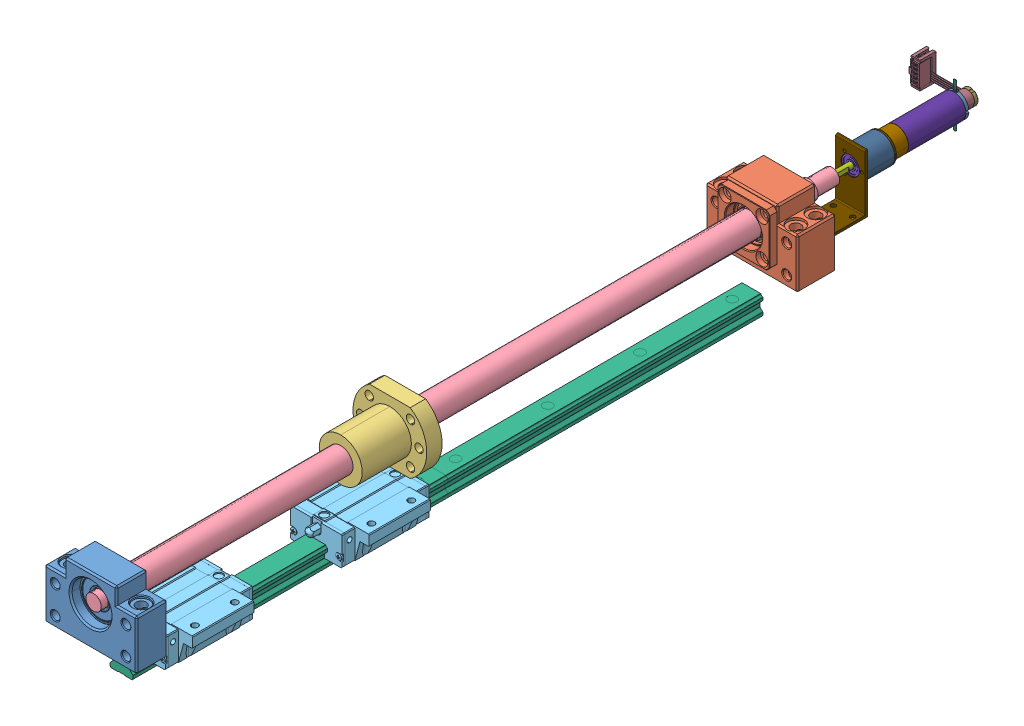
SolidWorks assembly ScrewAssembly_15cm_SIDE - Copy, configuration Default. Lengths in mm.
Overall size (61 69.4 574.65).
21 component instances, 18 part files, 27 mates.
Components (placement in the parent):
- BF12.step-1: BF12.step [Default] at (-30 0 240.25) size (60 43 20)
- BK12.step-1: BK12.step [Default] at (-30 0 -192.5) size (60 43 30.65)
- RM1605 Ball Nut STEP.step-1: RM1605 Ball Nut STEP.step [Default] at (-30 25 45.3506) x (0 0 1) z (0 -1 0) size (42 48 40)
- RM1605-1: RM1605 [Default] at (-30 25 248.25) x (-0.470167 -0.882577 0) z (0 0 -1) size (16 16 480.75)
- Carriage-1: Carriage [Default] at (-30 -24.4 145.8326) x (1 0 0) z (0 1 0) size (52 63.99 19.5)
- Rail-1: Rail [Default] at (-30 -24.4 230) x (1 0 0) z (0 1 0) size (15 205 12.5)
- Gantry Motor.stp-1: Gantry Motor.stp [Default] at (-30 25 -246) x (0 0 -1) z (1 0 0) size (91.9 29 40.5)
  - 0.stp-1: 0.stp [Default] at origin size (14.5 4 4)
  - 0-0.stp-1: 0-0.stp [Default] at origin size (4 12 12)
  - 0-1.stp-1: 0-1.stp [Default] at origin size (10.45 19 19)
  - 0-2.stp-1: 0-2.stp [Default] at origin size (17.97 19 19)
  - 0-3.stp-1: 0-3.stp [Default] at origin size (0.5 9.2 9.2)
  - 0-4.stp-1: 0-4.stp [Default] at origin size (2.88 10 10)
  - 0-5.stp-1: 0-5.stp [Default] at origin size (10.9 17.48 36)
  - 0-6.stp-1: 0-6.stp [Default] at origin size (2 15.64 15.71)
  - 0-7.stp-1: 0-7.stp [Default] at origin size (2.2 29 2.3)
  - 0-8.stp-1: 0-8.stp [Default] at origin size (2.1 15.8 15.45)
  - 0-9.stp-1: 0-9.stp [Default] at origin size (37.3 16 16)
- Motor Mounting Bracket-1: Motor Mounting Bracket [8982K701] at (-20.5 0 -226.95) x (0 0 -1) z (1 0 0) size (38.1 38.1 19)
- Rail-2: Rail [Default] at (-30 -24.4 25) x (1 0 0) z (0 1 0) size (15 205 12.5)
- Carriage-2: Carriage [Default] at (-30 -24.4 260.7326) x (1 0 0) z (0 1 0) size (52 63.99 19.5)
Mates (geometry in assembly coordinates):
- Coincident5: coincident: plane of assembly through (0 0 0) normal (0 1 0); plane of BK12.step-1 through (-60 0 -180) normal (0 -1 0); plane of assembly
- Coincident6: coincident: plane of assembly through (0 0 0) normal (0 1 0); plane of BF12.step-1 through (-60 0 250.25) normal (0 -1 0); plane of assembly
- Coincident8: coincident: plane of assembly through (0 0 0) normal (1 0 0); plane of BK12.step-1 through (0 0 -180) normal (1 0 0); plane of assembly
- Concentric7: concentric: cylinder of RM1605 Ball Nut STEP.step-1 through (-30 25 45.3506) axis (0 0 1) radius 8; cylinder of RM1605-1 through (-30 25 248.25) axis (0 0 1) radius 8
- Concentric8: concentric: cylinder of BK12.step-1 through (-30 25 -157.1571) axis (0 0 1) radius 6; cylinder of RM1605-1 through (-30 25 248.25) axis (0 0 1) radius 8
- Concentric9: concentric: cylinder of BF12.step-1 through (-30 25 244.456) axis (0 0 1) radius 5; cylinder of RM1605-1 through (-30 25 248.25) axis (0 0 1) radius 5
- Coincident11: coincident: plane of BF12.step-1 through (-30 30 236.25) normal (0 0 -1); plane of RM1605-1 through (-37.0606 28.7613 236.25) normal (0 0 1)
- Width1: width anti-aligned: plane of Carriage-1 through (-22.5 -14.3 31.1516) normal (-1 0 0); plane of Carriage-1 through (-37.5 -14.3 31.1516) normal (1 0 0); plane of Rail-1 through (-22.5 -14.3 25) normal (1 0 0); plane of Rail-1 through (-37.5 -14.3 25) normal (-1 0 0)
- Coincident22: coincident anti-aligned: plane of Carriage-1 through (-30 -11.9 31.1516) normal (0 -1 0); plane of Rail-1 through (-30 -11.9 25) normal (0 1 0)
- Coincident23: coincident: plane of RM1605 Ball Nut STEP.step-1 through (-30 25 45.3506) normal (0 0 -1); point of Carriage-1
- Width2: width: plane of BK12.step-1 through (0 0 -180) normal (1 0 0); plane of BK12.step-1 through (-60 32.5 -180) normal (-1 0 0); plane of Carriage-1 through (-56 -3.4 74.9316) normal (-1 0 0); plane of Carriage-1 through (-4 -3.9 55.0316) normal (1 0 0)
- Distance1: distance = 25.4 mm: cylinder of RM1605 Ball Nut STEP.step-1 through (-30 25 87.3506) axis (0 0 -1) radius 14; plane of Carriage-1 through (-30 -0.4 55.0316) normal (0 1 0)
- Concentric10: concentric aligned: cylinder of RM1605-1 through (-30 25 248.25) axis (0 0 1) radius 5; cylinder of Gantry Motor.stp-1/0.stp-1 through (-30 25 -239.75) axis (0 0 1) radius 2
- Parallel1: parallel: plane of BK12.step-1 through (-60 32.5 -180) normal (-1 0 0); plane of Gantry Motor.stp-1/0-5.stp-1 through (-60 21.83 -320.7) normal (-1 0 0)
- Coincident26: coincident anti-aligned: plane of RM1605-1 through (-30 25 -232.5) normal (0 0 -1); plane of Gantry Motor.stp-1/0.stp-1 through (-30 25 -232.5) normal (0 0 1)
- Coincident27: coincident anti-aligned: plane of Gantry Motor.stp-1/0-2.stp-1 through (-22.25 25 -246) normal (0 0 1); plane of Motor Mounting Bracket-1 through (-39.5 0 -246) normal (0 0 -1)
- Concentric11: concentric aligned: cylinder of Gantry Motor.stp-1/0-0.stp-1 through (-30 25 -246.75) axis (0 0 -1) radius 6; cylinder of Motor Mounting Bracket-1 through (-30 25 -207.899) axis (0 0 -1) radius 5.9995
- Coincident28: coincident: plane of BK12.step-1 through (-60 0 -180) normal (0 -1 0); plane of Motor Mounting Bracket-1 through (-39.5 0 -207.9) normal (0 -1 0)
- Parallel2: parallel: plane of BK12.step-1 through (-13 43 -180) normal (0 1 0); plane of RM1605 Ball Nut STEP.step-1 through (-54 45 45.3506) normal (0 1 0)
- Distance2: distance = 174.8994 mm: plane of RM1605 Ball Nut STEP.step-1 through (-30 25 55.3506) normal (0 0 1); plane of BF12.step-1 through (-60 0 230.25) normal (0 0 -1)
- Coincident29: coincident anti-aligned: plane of Rail-1 through (-30 -18.2514 25) normal (0 0 -1); plane of Rail-2 through (-30 -18.2514 25) normal (0 0 1)
- Coincident30: coincident aligned: plane of Rail-1 through (-30 -11.9 25) normal (0 1 0); plane of Rail-2 through (-30 -11.9 -180) normal (0 1 0)
- Coincident31: coincident aligned: plane of Rail-1 through (-24.5 -18.4969 25) normal (1 0 0); plane of Rail-2 through (-24.5 -18.4969 -180) normal (1 0 0)
- Coincident32: coincident: plane of BK12.step-1 through (-30 32.65 -178.5) normal (0 0 1); plane of RM1605-1 through (-35.2955 27.821 -178.5) normal (0 0 -1)
- Coincident33: coincident aligned: plane of Carriage-1 through (-4 -3.9 55.0316) normal (1 0 0); plane of Carriage-2 through (-4 -3.9 169.9316) normal (1 0 0)
- Coincident34: coincident aligned: plane of Carriage-1 through (-30 -0.4 55.0316) normal (0 1 0); plane of Carriage-2 through (-30 -0.4 169.9316) normal (0 1 0)
- Distance4: distance = 88.9 mm: cylinder of Carriage-2 through (-9.5 -3.9 176.8316) axis (0 -1 0) radius 2.1; cylinder of Carriage-1 through (-9.5 -3.9 87.9316) axis (0 -1 0) radius 2.1
